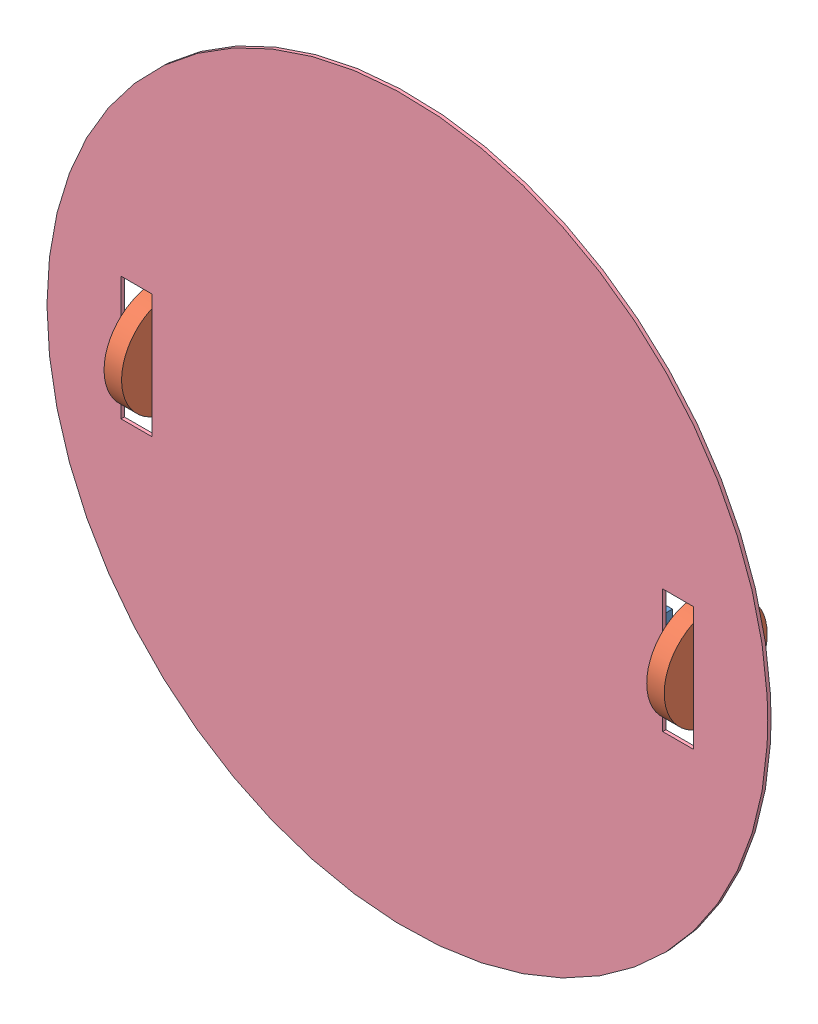
SolidWorks assembly suspension assembly, configuration Default. Lengths in mm.
Overall size (350 350 50).
5 component instances, 4 part files, 8 mates.
Components (placement in the parent):
- axle-1: axle [Default] at (56.872 125.0338 147.0856) size (255 20 5)
- wheel 50mm-1: wheel 50mm [Default] at (296.872 135.0338 149.5856) x (0 0 -1) z (1 0 0) size (50 50 18.5)
- wheel 50mm-2: wheel 50mm [Default] at (41.872 135.0338 149.5856) x (0 0 1) z (-1 0 0) size (50 50 18.5)
- DC motor-1: DC motor [Default] at (105.072 135.0338 138.4254) x (0 -0.937549 -0.347854) z (0 0.347854 -0.937549) size (20 61.2 20)
- base-1: base [Default] at (169.372 137.3843 161.7205) size (350 350 1.6)
Mates (geometry in assembly coordinates):
- Concentric1: concentric anti-aligned: cylinder of axle-1 through (296.872 135.0338 149.5856) axis (-1 0 0) radius 2.5; cylinder of wheel 50mm-1 through (286.872 135.0338 149.5856) axis (1 0 0) radius 2.5
- Coincident1: coincident anti-aligned: plane of axle-1 through (296.872 135.0338 149.5856) normal (1 0 0); plane of wheel 50mm-1 through (296.872 135.0338 149.5856) normal (-1 0 0)
- Concentric2: concentric anti-aligned: cylinder of axle-1 through (41.872 135.0338 149.5856) axis (1 0 0) radius 2.5; cylinder of wheel 50mm-2 through (51.872 135.0338 149.5856) axis (-1 0 0) radius 2.5
- Coincident2: coincident anti-aligned: plane of axle-1 through (41.872 135.0338 149.5856) normal (-1 0 0); plane of wheel 50mm-2 through (41.872 135.0338 149.5856) normal (1 0 0)
- Coincident3: coincident: line of axle-1 through (61.872 130.0338 147.0856) axis (1 0 0); cylinder of DC motor-1 through (64.7233 135.0338 138.4254) axis (1 0 0) radius 10
- Coincident4: coincident: line of axle-1 through (276.872 140.0338 147.0856) axis (-1 0 0); cylinder of DC motor-1 through (64.7233 135.0338 138.4254) axis (1 0 0) radius 10
- Distance1: distance = 3.5 mm anti-aligned: plane of wheel 50mm-2 through (41.872 135.0338 149.5856) normal (1 0 0); plane of base-1 through (45.372 167.3843 161.7205) normal (-1 0 0)
- Coincident6: coincident anti-aligned: plane of axle-1 through (61.872 130.0338 147.0856) normal (1 0 0); plane of DC motor-1 through (61.872 135.0338 138.4254) normal (-1 0 0)
